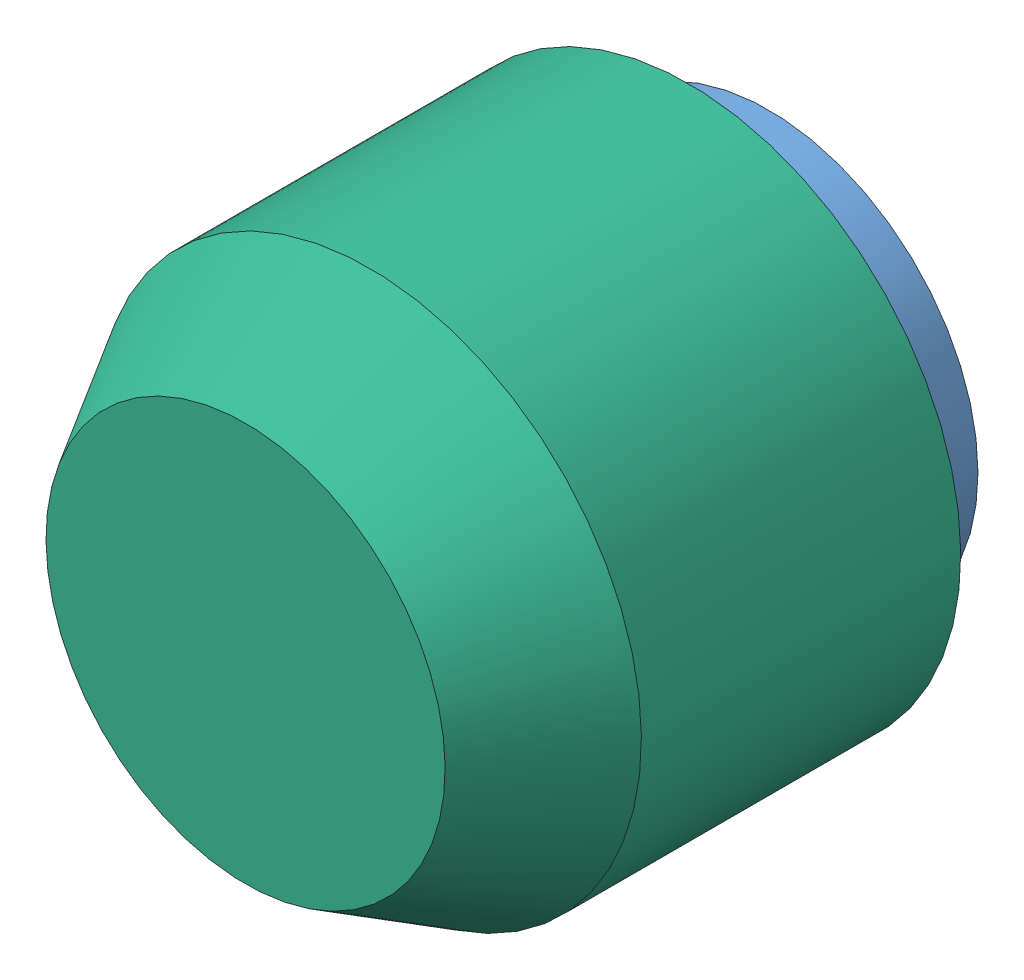
SolidWorks assembly Full Lock Assembly, configuration Default. Lengths in mm.
Overall size (82.49 82.49 66.5).
6 component instances, 6 part files, 11 mates.
Components (placement in the parent):
- Backplate-1: Backplate [Default] at (-0.0035 9.25 -6) x (1 0.000375 0) z (0 0 1) size (63.38 63.37 47.63)
- Servo Tower Pro 9G SG90-1: Servo Tower Pro 9G SG90 [Défaut] at (-5.7561 16.2478 47.6) x (-0.000375 1 0) z (0 0 -1) size (32 11.7 29.7)
- Lock Shaft Adapter-1: Lock Shaft Adapter [Default] at (0 0 13) x (0 0 -1) z (0.998605 -0.052804 0) size (30 10 11.55)
- Mini Servo Shaft Adapter-1: Mini Servo Shaft Adapter [Default] at (0 0 8.5) x (0 0 1) z (0.998605 -0.052804 0) size (12 16 16)
- Particle Photon-1: Particle Photon [Default] at (-0.0042 26.3324 10.3579) size (37.61 4.58 20.42)
- Cover-1: Cover [Default] at (-0.0035 9.25 -6) x (0 0 1) z (-0.971061 0.238833 0) size (56.75 68.18 68.18)
Mates (geometry in assembly coordinates):
- Coincident11: coincident: point of Backplate-1; point of assembly
- Distance2: distance = 10 mm anti-aligned: plane of Lock Shaft Adapter-1 through (0 0 10) normal (0 0 -1); plane of Backplate-1 through (-0.0035 9.25 0) normal (0 0 1)
- Concentric2: concentric anti-aligned: cylinder of Lock Shaft Adapter-1 through (0 0 -17) axis (0 0 1) radius 4.75; cylinder of Mini Servo Shaft Adapter-1 through (0 0 16.5) axis (0 0 -1) radius 3
- Parallel1: parallel anti-aligned: plane of Lock Shaft Adapter-1 through (5.7654 -0.3049 10) normal (0.891219 0.453573 0); plane of Mini Servo Shaft Adapter-1 through (3.5244 5.4215 14.5) normal (-0.891219 -0.453573 0)
- Concentric3: concentric anti-aligned: cylinder of Backplate-1 through (0 0 0) axis (0 0 -1) radius 5.15; cylinder of Lock Shaft Adapter-1 through (0 0 -17) axis (0 0 1) radius 4.75
- Distance3: distance = 1.5 mm anti-aligned: plane of Lock Shaft Adapter-1 through (0 0 13) normal (0 0 1); plane of Mini Servo Shaft Adapter-1 through (0 0 14.5) normal (0 0 -1)
- Concentric5: concentric aligned: cylinder of Servo Tower Pro 9G SG90-1 through (0 0 17.9) axis (0 0 1) radius 2.5; cylinder of Mini Servo Shaft Adapter-1 through (0 0 17.9) axis (0 0 1) radius 2.4
- Coincident10: coincident anti-aligned: plane of Servo Tower Pro 9G SG90-1 through (0 0 17.9) normal (0 0 -1); plane of Mini Servo Shaft Adapter-1 through (0 0 17.9) normal (0 0 1)
- Parallel2: parallel: line of Backplate-1 through (50000 -0.0035 9.25) axis (0 0.000375 -1); plane of Servo Tower Pro 9G SG90-1 through (-5.7561 16.2478 25.1) normal (-1 -0.000375 0)
- Concentric6: concentric aligned: cylinder of Backplate-1 through (-0.0035 9.25 0) axis (0 0 -1) radius 31.685; cylinder of Cover-1 through (-0.0035 9.25 34) axis (0 0 -1) radius 32.09
- Coincident12: coincident aligned: plane of Backplate-1 through (-0.0035 9.25 -6) normal (0 0 -1); plane of Cover-1 through (-0.0035 9.25 -6) normal (0 0 -1)
